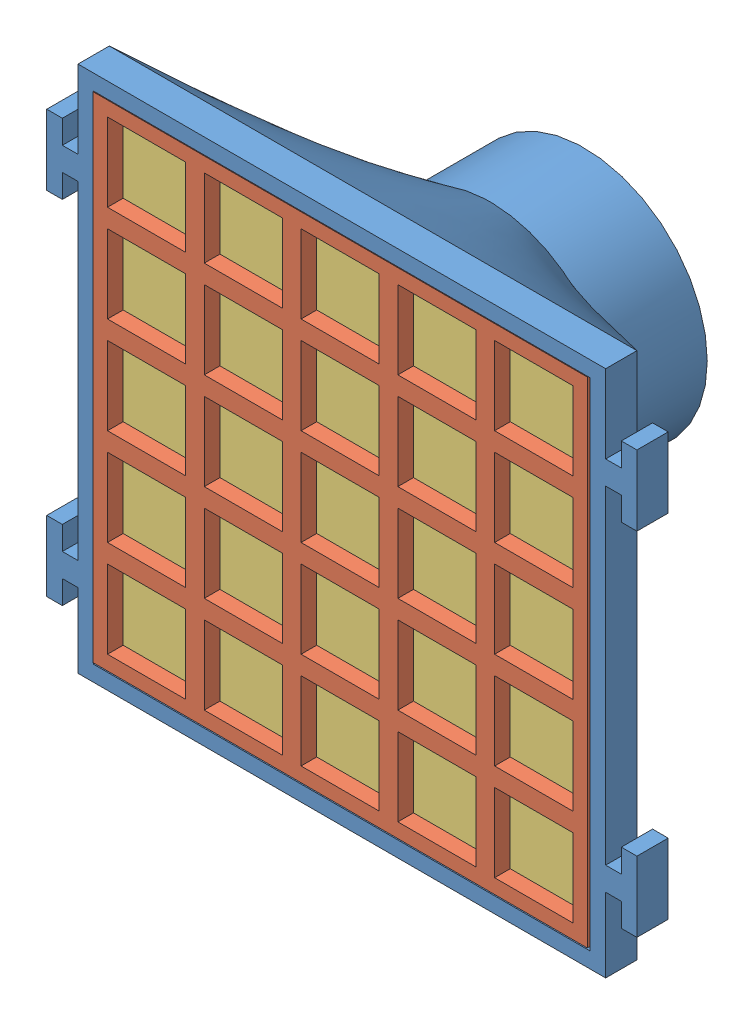
SolidWorks assembly Assembled_Unit, configuration Default. Lengths in mm.
Overall size (75.5 67.5 31.1).
4 component instances, 3 part files, 5 mates.
Components (placement in the parent):
- funnel-1: funnel [Default] at (41.2966 60.1554 43.1375) size (75.5 67.5 31)
- grill-1: grill [Default] at (41.2966 49.8054 58.1375) x (1 0 0) z (0 -1 0) size (63.25 2 63.25)
- grill-2: grill [Default] at (41.0466 50.0554 60.2375) x (1 0 0) z (0 -1 0) size (63.25 2 63.25)
- filter-1: filter [Default] at (41.2966 50.0554 60.1375) size (63.5 63.5 0.1)
Mates (geometry in assembly coordinates):
- Coincident7: coincident: line of funnel-1 through (9.5466 18.3054 62.1375) axis (0 0 -1); point of filter-1
- Coincident11: coincident anti-aligned: plane of funnel-1 through (41.2966 60.1554 58.1375) normal (0 0 1); plane of grill-1 through (41.2966 49.8054 58.1375) normal (0 0 -1)
- Coincident12: coincident: point of funnel-1; point of grill-1
- Coincident13: coincident aligned: line of funnel-1 through (73.0466 18.3054 62.1375) axis (0 0 -1); line of filter-1 through (73.0466 18.3054 60.2375) axis (0 0 -1)
- Coincident14: coincident: point of grill-2; point of filter-1
